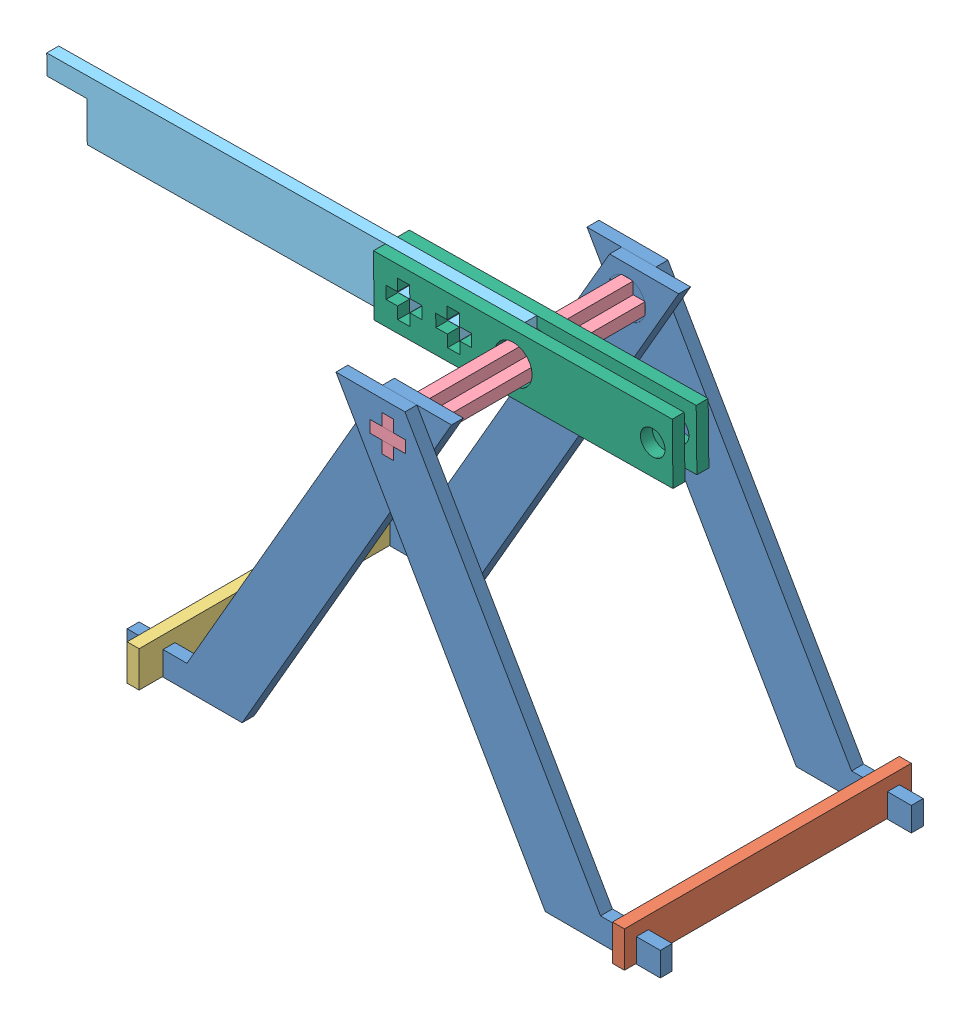
SolidWorks assembly Assemblage1, configuration Défaut. Lengths in mm.
Overall size (188.48 91.46 72).
13 component instances, 6 part files, 18 mates.
Components (placement in the parent):
- Frame_Truss-1: Frame_Truss [Défaut] at (8.4093 51.7581 91) size (81.4 91 3)
- Frame_Truss-2: Frame_Truss [Défaut] at (17.0519 51.7581 91) x (-1 0 0) z (0 0 -1) size (81.4 91 3)
- Frame_Truss-3: Frame_Truss [Défaut] at (8.4093 51.7581 148) size (81.4 91 3)
- Frame_Truss-4: Frame_Truss [Défaut] at (17.0519 51.7581 154) x (-1 0 0) z (0 0 -1) size (81.4 91 3)
- Frame_SideBraces-1: Frame_SideBraces [Défaut] at (75.1267 -34.5739 121) x (0 0 -1) z (-1 0 0) size (72 9 3)
- Frame_SideBraces_Wide-1: Frame_SideBraces_Wide [Défaut] at (-46.6655 -34.5739 121) x (0 0 -1) z (-1 0 0) size (72 9 3)
- Fulcrum-1: Fulcrum [Défaut] at (-65.3694 47.4397 117.2087) x (0 0 -1) z (1 0 0) size (66 9 9)
  - Fulcrum-1: Fulcrum [Défaut] at (-3.7913 -3.1969 76.6) size (66 9 3)
  - Fulcrum-2: Fulcrum [Défaut] at (-3.7913 -1.6969 78.1) x (-1 0 0) z (0 -1 0) size (66 9 3)
- Throwing Arm-1: Throwing Arm [Défaut] at (-16.6035 47.2922 -2) x (0.99993 0.011796 0) z (0 0 1) size (160 15 9)
  - Throwing Arm-1: Throwing Arm [Défaut] at (-30.7039 -3.3951 118.5) size (120 15 3)
  - Throwing Arm_Lower-1: Throwing Arm_Lower [Défaut] at (41.7961 -3.3951 115.5) size (75 15 3)
  - Throwing Arm_Lower-2: Throwing Arm_Lower [Défaut] at (41.7961 -3.3951 121.5) size (75 15 3)
Mates (geometry in assembly coordinates):
- Coïncidente1: coincident anti-aligned: plane of Frame_Truss-3 through (8.4093 51.7581 151) normal (0 0 1); plane of Frame_Truss-4 through (17.0519 51.7581 151) normal (0 0 -1)
- Coïncidente2: coincident aligned: plane of Frame_Truss-3 through (8.4093 51.7581 151) normal (0 1 0); plane of Frame_Truss-4 through (17.0519 51.7581 151) normal (0 1 0)
- Coïncidente3: coincident aligned: plane of Frame_Truss-3 through (8.2306 51.7581 151) normal (1 0 0); plane of Frame_Truss-4 through (8.2306 51.7581 151) normal (1 0 0)
- Coïncidente5: coincident aligned: plane of Frame_Truss-1 through (17.2306 51.7581 94) normal (-1 0 0); plane of Frame_Truss-2 through (17.2306 51.7581 88) normal (-1 0 0)
- Coïncidente6: coincident aligned: plane of Frame_Truss-1 through (8.4093 51.7581 94) normal (0 1 0); plane of Frame_Truss-2 through (17.0519 51.7581 88) normal (0 1 0)
- Coïncidente9: coincident anti-aligned: plane of Frame_Truss-4 through (17.0519 -36.0739 151) normal (0 1 0); plane of Frame_SideBraces-1 through (72.1267 -36.0739 154) normal (0 -1 0)
- Coïncidente10: coincident anti-aligned: plane of Frame_Truss-4 through (72.1267 51.7581 151) normal (1 0 0); plane of Frame_SideBraces-1 through (72.1267 -34.5739 121) normal (-1 0 0)
- Coïncidente11: coincident anti-aligned: plane of Frame_Truss-4 through (17.0519 51.7581 154) normal (0 0 1); plane of Frame_SideBraces-1 through (72.1267 -39.0739 154) normal (0 0 -1)
- Coïncidente12: coincident anti-aligned: plane of Frame_Truss-1 through (8.4093 51.7581 91) normal (0 0 -1); plane of Frame_Truss-2 through (17.0519 51.7581 91) normal (0 0 1)
- Coïncidente13: coincident anti-aligned: plane of Frame_Truss-2 through (17.0519 51.7581 88) normal (0 0 -1); plane of Frame_SideBraces-1 through (72.1267 -39.0739 88) normal (0 0 1)
- Coïncidente14: coincident anti-aligned: plane of Frame_Truss-3 through (8.4093 -36.0739 151) normal (0 1 0); plane of Frame_SideBraces_Wide-1 through (-49.6655 -36.0739 151) normal (0 -1 0)
- Coïncidente15: coincident anti-aligned: plane of Frame_Truss-3 through (8.4093 51.7581 151) normal (0 0 1); plane of Frame_SideBraces_Wide-1 through (-49.6655 -39.0739 151) normal (0 0 -1)
- Coïncidente16: coincident anti-aligned: plane of Frame_Truss-3 through (-46.6655 51.7581 151) normal (-1 0 0); plane of Frame_SideBraces_Wide-1 through (-46.6655 -34.5739 121) normal (1 0 0)
- Coïncidente17: coincident: plane of Frame_Truss-4 through (17.0519 51.7581 154) normal (0 0 1); plane of Fulcrum-1/Fulcrum-1 through (14.2306 48.7429 154) normal (0 0 1)
- Coïncidente18: coincident: plane of Frame_Truss-4 through (17.0519 48.7429 151) normal (0 -1 0); plane of Fulcrum-1/Fulcrum-1 through (14.2306 48.7429 154) normal (0 1 0)
- Coïncidente19: coincident: plane of Frame_Truss-4 through (17.2306 51.7581 151) normal (-1 0 0); plane of Fulcrum-1/Fulcrum-2 through (17.2306 42.7429 88) normal (1 0 0)
- Coaxiale1: concentric: circle of Frame_Truss-2; circle of Throwing Arm-1/Throwing Arm_Lower-1
- Distance1: distance = 25.5 mm: plane of Frame_Truss-3 through (8.4093 51.7581 148) normal (0 0 -1); plane of Throwing Arm-1/Throwing Arm_Lower-2 through (25.2306 44.2429 122.5) normal (0 0 1)
